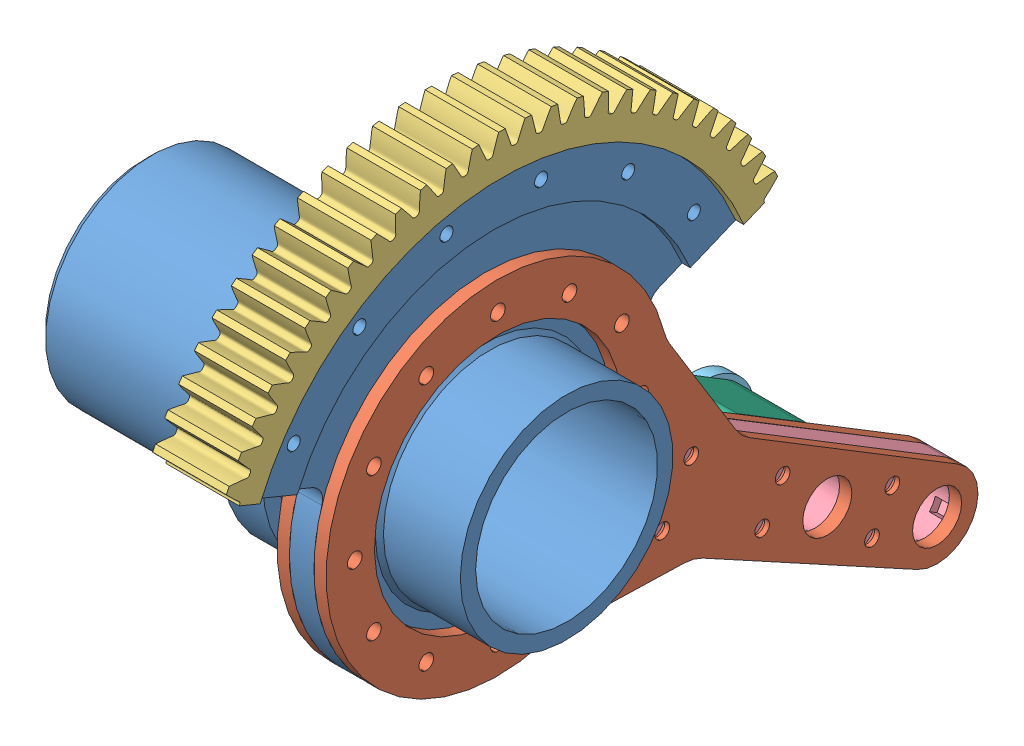
SolidWorks assembly hip-front-new-right-2012-09-04, configuration Default. Lengths in mm.
Overall size (51.7 100 168.18).
7 component instances, 6 part files, 17 mates.
Components (placement in the parent):
- abs-hip-front-2012-11-20-1: abs-hip-front-2012-11-20 [Default] at (-57.0839 1.2367 -1.8747) size (51.7 53 129.22)
- carbon-plat-hip-front-1: carbon-plat-hip-front [Default] at (-60.0839 1.2367 -1.8747) x (0 -0.5 -0.866025) z (1 0 0) size (88 42 1.5)
- carbon-plat-hip-front-2: carbon-plat-hip-front [Default] at (-55.5839 1.2367 -1.8747) x (0 -0.5 -0.866025) z (1 0 0) size (88 42 1.5)
- Part3-1: Part3 [Default] at (-58.0839 1.2367 -1.8747) x (1 0 0) z (0 -0.382683 -0.92388) size (9 71.48 71.48)
- Pom-plat-hip-front-04-03-13-3: Pom-plat-hip-front-04-03-13 [Default] at (-58.5839 1.2367 -1.8747) x (0 -0.5 -0.866025) z (1 0 0) size (49.97 22.69 3)
- Washer-d6p5-12-1: Washer-d6p5-12 [Défaut] at (-69.7839 -22.0133 -42.1449) x (0 -0.710401 0.703797) z (-1 0 0) size (12 12 1.6)
- distancepiece_legsprings_011112_Mill_Pom-1: distancepiece_legsprings_011112_Mill_Pom [Default] at (-64.5339 -22.0133 -42.1449) x (0 -0.866025 0.5) z (-1 0 0) size (11.24 15.4 8.9)
Mates (geometry in assembly coordinates):
- Coincident1: coincident anti-aligned: plane of abs-hip-front-2012-11-20-1 through (-58.5839 6.2116 10.1357) normal (-1 0 0); plane of carbon-plat-hip-front-1 through (-58.5839 -29.7633 -55.5683) normal (1 0 0)
- Concentric1: concentric aligned: cylinder of abs-hip-front-2012-11-20-1 through (-57.0839 1.2367 -1.8747) axis (-1 0 0) radius 13; cylinder of carbon-plat-hip-front-1 through (-58.5839 1.2367 -1.8747) axis (-1 0 0) radius 15.1
- Concentric2: concentric aligned: cylinder of abs-hip-front-2012-11-20-1 through (-57.0839 1.2367 -1.8747) axis (-1 0 0) radius 13; cylinder of carbon-plat-hip-front-2 through (-54.0839 1.2367 -1.8747) axis (-1 0 0) radius 15.1
- Coincident2: coincident anti-aligned: plane of abs-hip-front-2012-11-20-1 through (-55.5839 6.2116 10.1357) normal (1 0 0); plane of carbon-plat-hip-front-2 through (-55.5839 -29.7633 -55.5683) normal (-1 0 0)
- Concentric3: concentric aligned: cylinder of carbon-plat-hip-front-1 through (-58.5839 -29.7633 -55.5683) axis (-1 0 0) radius 3; cylinder of carbon-plat-hip-front-2 through (-54.0839 -29.7633 -55.5683) axis (-1 0 0) radius 3
- Concentric4: concentric anti-aligned: cylinder of abs-hip-front-2012-11-20-1 through (-57.0839 1.2367 -1.8747) axis (-1 0 0) radius 32; cylinder of Part3-1 through (-59.5839 1.2367 -1.8747) axis (1 0 0) radius 32
- Coincident7: coincident anti-aligned: plane of abs-hip-front-2012-11-20-1 through (-59.5839 13.4826 27.6894) normal (-1 0 0); plane of Part3-1 through (-59.5839 25.2576 -11.8245) normal (1 0 0)
- Coincident8: coincident aligned: plane of abs-hip-front-2012-11-20-1 through (-58.5839 13.4826 -31.4389) normal (0 -0.92388 -0.382683); plane of Part3-1 through (-62.5839 1.2367 -1.8747) normal (0 -0.92388 -0.382683)
- Concentric7: concentric anti-aligned: cylinder of abs-hip-front-2012-11-20-1 through (-58.5839 9.9867 -17.0302) axis (-1 0 0) radius 0.625; cylinder of carbon-plat-hip-front-1 through (-58.5839 9.9867 -17.0302) axis (1 0 0) radius 0.9
- Coïncidente2: coincident anti-aligned: plane of carbon-plat-hip-front-2 through (-55.5839 -29.7633 -55.5683) normal (-1 0 0); plane of Pom-plat-hip-front-04-03-13-3 through (-55.5839 -29.7633 -55.5683) normal (1 0 0)
- Coaxiale1: concentric aligned: cylinder of carbon-plat-hip-front-2 through (-54.0839 -29.7633 -55.5683) axis (-1 0 0) radius 3; cylinder of Pom-plat-hip-front-04-03-13-3 through (-55.5839 -29.7633 -55.5683) axis (-1 0 0) radius 3
- Coaxiale2: concentric aligned: cylinder of carbon-plat-hip-front-2 through (-54.0839 -22.0133 -42.1449) axis (-1 0 0) radius 3; cylinder of Pom-plat-hip-front-04-03-13-3 through (-55.5839 -22.0133 -42.1449) axis (-1 0 0) radius 3
- Coaxiale3: concentric anti-aligned: cylinder of Pom-plat-hip-front-04-03-13-3 through (-55.5839 -22.0133 -42.1449) axis (-1 0 0) radius 3; cylinder of Washer-d6p5-12-1 through (-70.5839 -22.0133 -42.1449) axis (1 0 0) radius 3.25
- Coïncidente4: coincident anti-aligned: plane of carbon-plat-hip-front-1 through (-60.0839 -29.7633 -55.5683) normal (-1 0 0); plane of distancepiece_legsprings_011112_Mill_Pom-1 through (-60.0839 -22.0133 -42.1449) normal (1 0 0)
- Coaxiale4: concentric aligned: cylinder of Pom-plat-hip-front-04-03-13-3 through (-55.5839 -20.3033 -34.1832) axis (1 0 0) radius 0.625; cylinder of distancepiece_legsprings_011112_Mill_Pom-1 through (-60.0839 -20.3033 -34.1832) axis (1 0 0) radius 0.625
- Coaxiale5: concentric aligned: cylinder of Pom-plat-hip-front-04-03-13-3 through (-55.5839 -15.9732 -36.6832) axis (1 0 0) radius 0.625; cylinder of distancepiece_legsprings_011112_Mill_Pom-1 through (-60.0839 -15.9732 -36.6832) axis (1 0 0) radius 0.625
- Coïncidente5: coincident anti-aligned: plane of Washer-d6p5-12-1 through (-68.9839 -22.0133 -42.1449) normal (1 0 0); plane of distancepiece_legsprings_011112_Mill_Pom-1 through (-68.9839 -22.0133 -42.1449) normal (-1 0 0)
